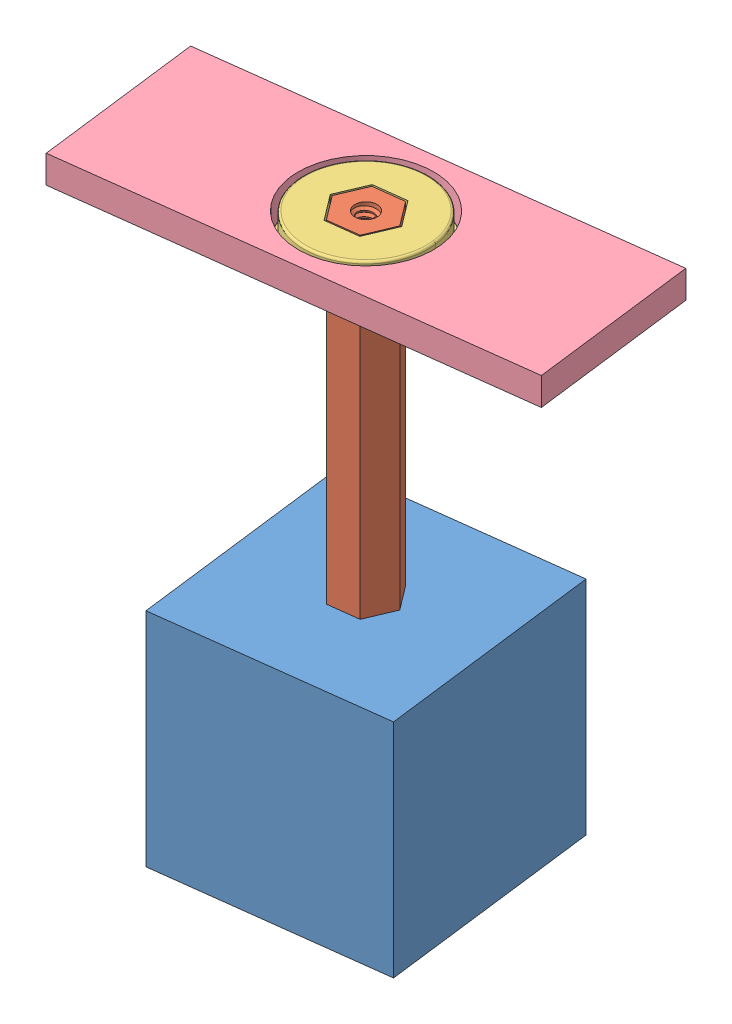
SolidWorks assembly climber prototype no arm, configuration Default. Lengths in mm.
Overall size (118.02 128.16 66.86).
4 component instances, 4 part files, 0 mates.
Components (placement in the parent):
- block for climber seprate-1: block for climber seprate [Default] at (1512.9894 926.808 1552.3982) x (0 1 0) z (0.992268 0 -0.124114) size (50.8 50.8 50.8)
- Hex shaft for climber-1: Hex shaft for climber [Default] at (1516.1419 914.108 1577.6018) x (0 1 0) z (0.992268 0 -0.124114) size (115.41 12 13.86)
- half in hex bearing for clibmer-2: half in hex bearing for clibmer [Default] at (1516.1419 1028.4613 1577.6018) x (0.992268 0 -0.124114) z (0 -1 0) size (31.12 31.12 7.93)
- wood piece for pivot in climber-1: wood piece for pivot in climber [Default] at (1516.1419 1022.058 1577.6018) x (0 1 0) z (0.992268 0 -0.124114) size (6.35 53.34 112.27)
